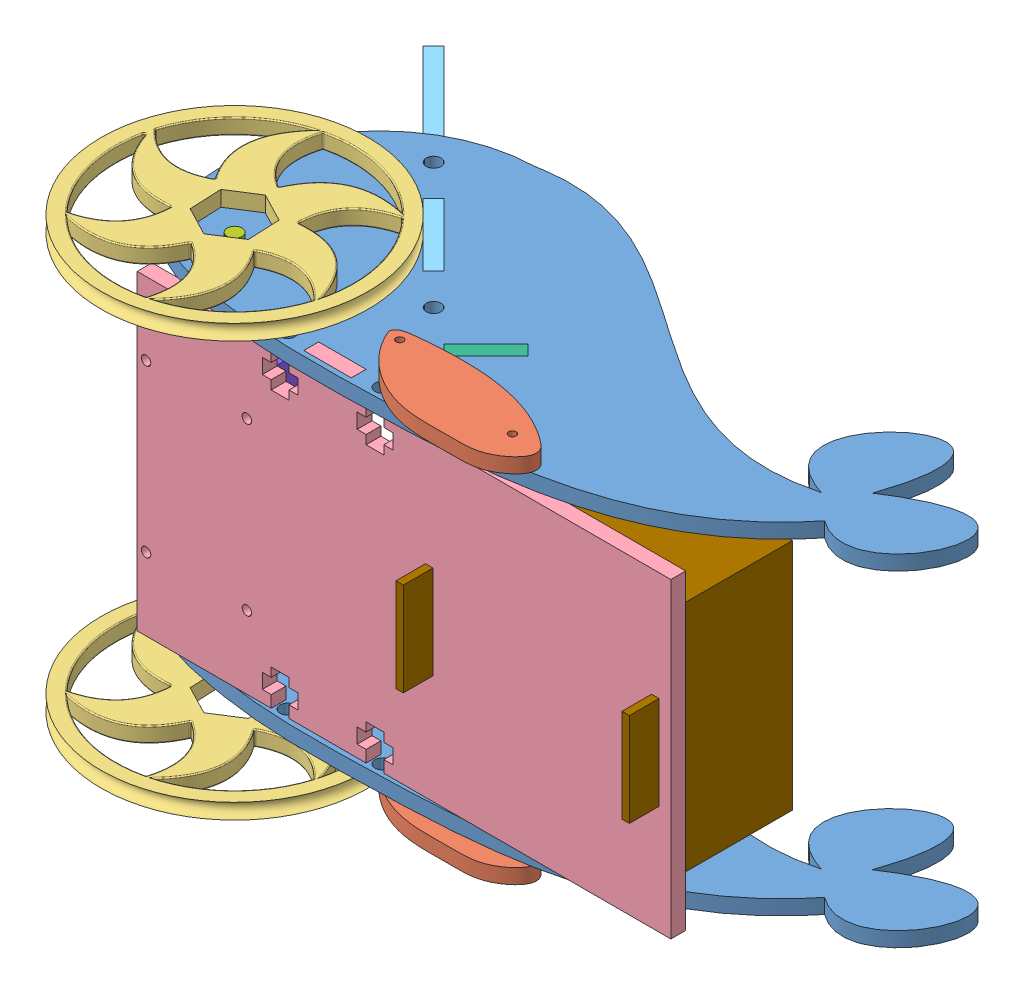
SolidWorks assembly Whale, configuration Default. Lengths in mm.
Overall size (285.38 93.7 118.51).
15 component instances, 9 part files, 30 mates.
Components (placement in the parent):
- Body-1: Body [Default] at (-1.6929 71.8989 159.1932) size (273.08 3.17 94.5)
- Fin-1: Fin [Default] at (0.5546 75.0739 158.1989) size (38.83 3.17 15.82)
- Fin-2: Fin [Default] at (0.5546 -1.1261 158.1989) size (38.83 3.17 15.82)
- Body-2: Body [Default] at (-1.6929 2.0489 159.1932) size (273.08 3.17 94.5)
- wheel-1: wheel [Default] at (18.128 81.4239 144.6737) x (-0.461035 0 0.887382) z (-0.887382 0 -0.461035) size (57.15 4.87 57.15)
- Base-2: Base [Default] at (5.428 71.8989 152.8398) x (1 0 0) z (0 1 0) size (114.3 3.18 73.03)
- Mount-1: Mount [Default] at (-27.552 -23.4024 111.4928) x (0.707107 0 0.707107) z (0 1 0) size (88.9 15.88 73.03)
  - phoneMount-1: phoneMount [Default] at (-6.5087 37.3881 95.3013) size (88.9 3.17 73.02)
  - phoneMount2-1: phoneMount2 [Default] at (79.2163 40.5631 98.4763) x (0 1 0) z (0 0 1) size (15.88 3.18 73.03)
- motor-1: motor [Default] at (11.778 71.8989 139.6826) x (0 -1 0) z (-1 0 0) size (34.92 9.98 12.7)
- motorMount-1: motorMount [Default] at (5.428 51.5789 149.2076) size (25.4 9.53 12.06)
- motorMount-2: motorMount [Default] at (30.828 25.5439 149.2076) x (-1 0 0) z (0 0 1) size (25.4 9.53 12.06)
- motor-3: motor [Default] at (24.478 5.2239 139.6826) x (0 1 0) z (1 0 0) size (34.92 9.98 12.7)
- wheel-2: wheel [Default] at (18.128 -7.4071 144.6737) x (-0.461035 0 0.887382) z (-0.887382 0 -0.461035) size (57.15 4.87 57.15)
- Board-2: Board [Default] at (117.188 13.5614 124.2648) x (0 1 0) z (1 0 0) size (50 34.93 50) (hidden)
Mates (geometry in assembly coordinates):
- Coincident2: coincident aligned: circle of Body-1; circle of Fin-1
- Coincident3: coincident aligned: circle of Body-1; circle of Fin-1
- Coincident4: coincident anti-aligned: plane of Body-2 through (76.4204 -4.3011 110.0102) normal (0 1 0); plane of ? through (-81.8274 -4.3011 139.995) normal (0 -1 0)
- Coincident8: coincident anti-aligned: plane of Body-1 through (76.4204 71.8989 110.0102) normal (0 -1 0); plane of Base-2 through (5.428 71.8989 149.6648) normal (0 1 0)
- Coincident9: coincident aligned: plane of Body-2 through (76.4204 2.0489 110.0102) normal (0 -1 0); plane of Base-2 through (5.428 2.0489 152.8398) normal (0 -1 0)
- Coincident10: coincident anti-aligned: plane of Body-2 through (41.1186 2.0489 159.1932) normal (1 0 0); plane of Base-2 through (41.1186 2.0489 152.8398) normal (-1 0 0)
- Coincident11: coincident anti-aligned: plane of Body-2 through (-1.6929 2.0489 149.6648) normal (0 0 1); plane of Base-2 through (5.428 71.8989 149.6648) normal (0 0 -1)
- Coincident12: coincident anti-aligned: plane of Body-2 through (76.4204 5.2239 110.0102) normal (0 1 0); plane of Mount-1/phoneMount-1 through (-3.4719 5.2239 78.208) normal (0 -1 0)
- Angle1: planar angle = 0.785398 rad anti-aligned: line of Mount-1/phoneMount-1 through (39.1843 75.0739 125.3543) axis (-0.707107 0 -0.707107); line of Base-2 through (5.428 71.8989 149.6648) axis (1 0 0)
- Distance1: distance = 6.35 mm: line of Mount-1/phoneMount-1 through (57.1448 71.8989 143.3148) axis (0 -1 0); plane of Base-2 through (5.428 71.8989 149.6648) normal (0 0 -1)
- Coincident21: coincident anti-aligned: plane of Base-2 through (5.428 71.8989 149.6648) normal (0 0 -1); plane of motor-1 through (11.778 71.8989 149.6648) normal (0 0 1)
- Coincident23: coincident anti-aligned: plane of Base-2 through (5.428 71.8989 149.6648) normal (0 0 -1); plane of motor-1 through (11.778 71.8989 149.6648) normal (0 0 1)
- Coincident24: coincident anti-aligned: plane of Base-2 through (5.428 71.8989 149.6648) normal (0 0 -1); plane of motor-1 through (11.778 71.8989 149.6648) normal (0 0 1)
- Coincident25: coincident anti-aligned: plane of Body-1 through (76.4204 71.8989 110.0102) normal (0 -1 0); plane of motor-1 through (11.778 71.8989 149.6648) normal (0 1 0)
- Coincident26: coincident anti-aligned: plane of Base-2 through (5.428 71.8989 149.6648) normal (0 0 -1); plane of ? through (24.478 8.3989 149.6648) normal (0 0 1)
- Coincident27: coincident anti-aligned: plane of Body-2 through (76.4204 8.3989 110.0102) normal (0 1 0); plane of ? through (24.478 8.3989 149.6648) normal (0 -1 0)
- Distance3: distance = 6.35 mm: line of ? through (11.778 33.7989 149.6648) axis (0 -1 0); line of Base-2 through (5.428 8.3989 149.6648) axis (0 1 0)
- Concentric1: concentric anti-aligned: circle of wheel-1; circle of motor-1
- Coincident29: coincident anti-aligned: plane of wheel-1 through (18.128 81.4239 144.6737) normal (0 -1 0); plane of motor-1 through (18.128 81.4239 144.6737) normal (0 1 0)
- Distance4: distance = 6.35 mm: line of Base-2 through (5.428 5.2239 149.6648) axis (0 1 0); line of motor-1 through (11.778 71.8989 149.6648) axis (0 -1 0)
- Coincident31: coincident anti-aligned: plane of motor-1 through (11.778 71.8989 139.6826) normal (0 0 -1); plane of motorMount-1 through (11.778 61.1039 139.6826) normal (0 0 1)
- Coincident32: coincident anti-aligned: plane of motor-1 through (11.778 71.8989 149.6648) normal (-1 0 0); plane of motorMount-1 through (11.778 61.1039 149.2076) normal (1 0 0)
- Distance5: distance = 5.08 mm aligned: plane of motor-1 through (11.778 46.4989 149.6648) normal (0 -1 0); plane of motorMount-1 through (5.428 51.5789 149.2076) normal (0 -1 0)
- Coincident35: coincident: plane of Base-2 through (5.428 71.8989 149.6648) normal (0 0 -1); plane of ? through (69.7281 16.1914 149.6648) normal (0 0 1)
- Distance9: distance = 0 mm: moEndPointRef_w of ?; line of Base-2 through (119.728 71.8989 149.6648) axis (0 -1 0)
- Coincident36: coincident anti-aligned: plane of Base-2 through (5.428 71.8989 149.6648) normal (0 0 -1); plane of Board-2 through (117.188 13.5614 149.6648) normal (0 0 1)
- Coincident39: coincident: moEndPointRef_w of Board-2; plane of assembly
- Parallel1: parallel aligned: line of Base-2 through (119.728 71.8989 149.6648) axis (0 -1 0); line of Board-2 through (67.1881 63.5613 124.2648) axis (0 -1 0)
- Distance11: distance = 2.54 mm aligned: plane of Base-2 through (119.728 71.8989 149.6648) normal (1 0 0); plane of Board-2 through (117.188 13.5614 149.6648) normal (1 0 0)
- Distance12: distance = 57.15 mm: line of Mount-1/phoneMount2-1 through (66.1251 75.0739 129.8444) axis (0 -1 0); line of Base-2 through (119.728 71.8989 149.6648) axis (0 -1 0)
